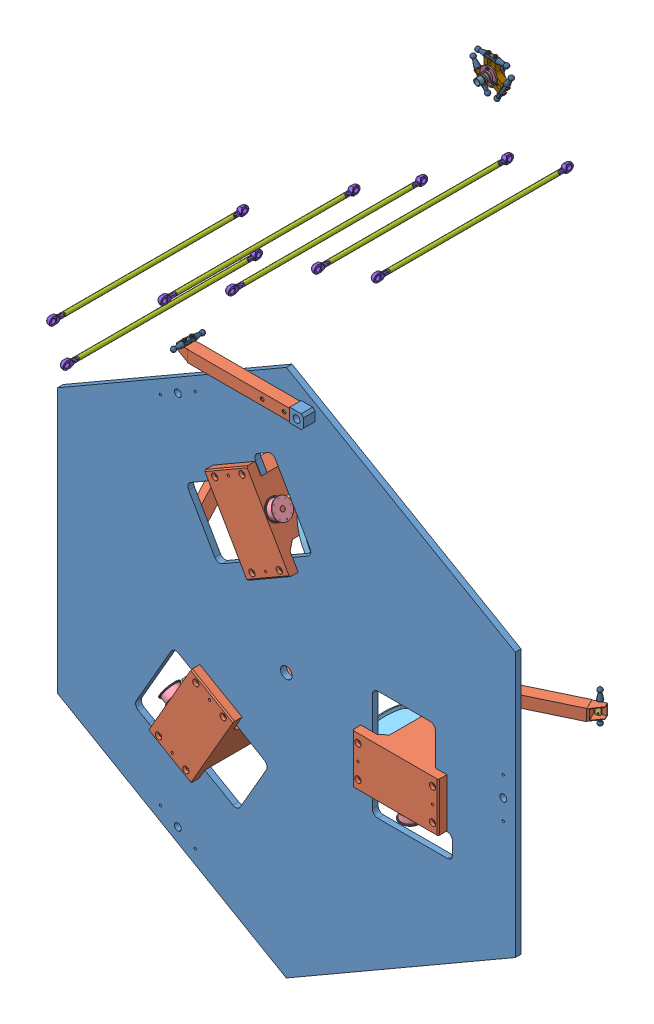
SolidWorks assembly RobotDelta, configuration Défaut. Lengths in mm.
Overall size (971.71 1045.23 749.16).
91 component instances, 22 part files, 18 mates.
Components (placement in the parent):
- Pièce0_Plaque-1: Pièce0_Plaque [Défaut] at origin size (798.48 922 10)
- BlocMoteur-2: BlocMoteur [Défaut] at (214 -99 -18) x (1 0 0) z (0 -1 0) size (260.5 181.1 163)
  - Pièce1_BlocMoteur-1: Pièce1_BlocMoteur [Défaut] at origin size (152.5 162.5 100)
  - Pièce1_PignionModifie-1: Pièce1_PignionModifie [Défaut] x (-0.683299 0.730139 0) z (0 0 1) size (16.65 16.65 16)
  - Pièce1_poulie_renvoie-1: Pièce1_poulie_renvoie [Défaut] at (0 26 0) size (34 34 15)
  - Pièce1_Roue-5: Pièce1_Roue [Défaut] at (-64 -97 0) x (0.958703 0.284409 0) z (0 0 1) size (209.95 116.72 12)
  - Pièce1_arbre-5: Pièce1_arbre [Défaut] at (-64 -97 -42.5) x (0.958703 0.284409 0) z (0 0 1) size (15 15 163)
- BlocMoteur-3: BlocMoteur [Défaut] at (-21.2635 234.8294 -18) x (-0.5 0.866025 0) z (0.866025 0.5 0) size (260.5 181.1 163)
  - Pièce1_BlocMoteur-1: Pièce1_BlocMoteur [Défaut] at origin size (152.5 162.5 100)
  - Pièce1_PignionModifie-1: Pièce1_PignionModifie [Défaut] x (-0.683299 0.730139 0) z (0 0 1) size (16.65 16.65 16)
  - Pièce1_poulie_renvoie-1: Pièce1_poulie_renvoie [Défaut] at (0 26 0) size (34 34 15)
  - Pièce1_Roue-5: Pièce1_Roue [Défaut] at (-64 -97 0) x (0.958703 0.284409 0) z (0 0 1) size (209.95 116.72 12)
  - Pièce1_arbre-5: Pièce1_arbre [Défaut] at (-64 -97 -42.5) x (0.958703 0.284409 0) z (0 0 1) size (15 15 163)
- BlocMoteur-4: BlocMoteur [Défaut] at (-192.7365 -135.8294 -18) x (-0.5 -0.866025 0) z (-0.866025 0.5 0) size (260.5 181.1 163)
  - Pièce1_BlocMoteur-1: Pièce1_BlocMoteur [Défaut] at origin size (152.5 162.5 100)
  - Pièce1_PignionModifie-1: Pièce1_PignionModifie [Défaut] x (-0.683299 0.730139 0) z (0 0 1) size (16.65 16.65 16)
  - Pièce1_poulie_renvoie-1: Pièce1_poulie_renvoie [Défaut] at (0 26 0) size (34 34 15)
  - Pièce1_Roue-5: Pièce1_Roue [Défaut] at (-64 -97 0) x (0.958703 0.284409 0) z (0 0 1) size (209.95 116.72 12)
  - Pièce1_arbre-5: Pièce1_arbre [Défaut] at (-64 -97 -42.5) x (0.958703 0.284409 0) z (0 0 1) size (15 15 163)
- BarreParalleles-6: BarreParalleles [Défaut] at (61.977 576.9928 -569.2096) size (11.85 14 348)
  - Pièce4_Tube-1: Pièce4_Tube [Défaut] at (-2.2142 0.2364 157) size (7 7 314)
  - Pièce4_Extremetees-1: Pièce4_Extremetees [Défaut] at (-2.2142 0.2364 147) x (0 -1 0) z (0 0 1) size (14 11.85 27)
  - Pièce4_Extremetees-2: Pièce4_Extremetees [Défaut] at (-2.2142 0.2364 481) x (0 1 0) z (0 0 -1) size (14 11.85 27)
- BarreParalleles-7: BarreParalleles [Défaut] at (-78.3246 502.1984 -605.2547) size (11.85 14 348)
  - Pièce4_Tube-1: Pièce4_Tube [Défaut] at (-2.2142 0.2364 157) size (7 7 314)
  - Pièce4_Extremetees-1: Pièce4_Extremetees [Défaut] at (-2.2142 0.2364 147) x (0 -1 0) z (0 0 1) size (14 11.85 27)
  - Pièce4_Extremetees-2: Pièce4_Extremetees [Défaut] at (-2.2142 0.2364 481) x (0 1 0) z (0 0 -1) size (14 11.85 27)
- BarreParalleles-8: BarreParalleles [Défaut] at (-192.8024 429.534 -570.0763) size (11.85 14 348)
  - Pièce4_Tube-1: Pièce4_Tube [Défaut] at (-2.2142 0.2364 157) size (7 7 314)
  - Pièce4_Extremetees-1: Pièce4_Extremetees [Défaut] at (-2.2142 0.2364 147) x (0 -1 0) z (0 0 1) size (14 11.85 27)
  - Pièce4_Extremetees-2: Pièce4_Extremetees [Défaut] at (-2.2142 0.2364 481) x (0 1 0) z (0 0 -1) size (14 11.85 27)
- BarreParalleles-9: BarreParalleles [Défaut] at (-314.684 352.2138 -574.0075) size (11.85 14 348)
  - Pièce4_Tube-1: Pièce4_Tube [Défaut] at (-2.2142 0.2364 157) size (7 7 314)
  - Pièce4_Extremetees-1: Pièce4_Extremetees [Défaut] at (-2.2142 0.2364 147) x (0 -1 0) z (0 0 1) size (14 11.85 27)
  - Pièce4_Extremetees-2: Pièce4_Extremetees [Défaut] at (-2.2142 0.2364 481) x (0 1 0) z (0 0 -1) size (14 11.85 27)
- BarreParalleles-10: BarreParalleles [Défaut] at (-485.1921 247.6485 -550.483) size (11.85 14 348)
  - Pièce4_Tube-1: Pièce4_Tube [Défaut] at (-2.2142 0.2364 157) size (7 7 314)
  - Pièce4_Extremetees-1: Pièce4_Extremetees [Défaut] at (-2.2142 0.2364 147) x (0 -1 0) z (0 0 1) size (14 11.85 27)
  - Pièce4_Extremetees-2: Pièce4_Extremetees [Défaut] at (-2.2142 0.2364 481) x (0 1 0) z (0 0 -1) size (14 11.85 27)
- BarreParalleles-11: BarreParalleles [Défaut] at (-563.2574 91.0819 -652.4845) size (11.85 14 348)
  - Pièce4_Tube-1: Pièce4_Tube [Défaut] at (-2.2142 0.2364 157) size (7 7 314)
  - Pièce4_Extremetees-1: Pièce4_Extremetees [Défaut] at (-2.2142 0.2364 147) x (0 -1 0) z (0 0 1) size (14 11.85 27)
  - Pièce4_Extremetees-2: Pièce4_Extremetees [Défaut] at (-2.2142 0.2364 481) x (0 1 0) z (0 0 -1) size (14 11.85 27)
- Nacelle-2: Nacelle [Défaut] at (-284.138 441.1633 -633.2721) size (78.36 68.86 48)
  - Pièce5_Nacelle-1: Pièce5_Nacelle [Défaut] at origin size (49.34 42.73 10)
  - Pièce2_Articulation-1: Pièce2_Articulation [Défaut] at (-20.7846 -12 0) x (-0.5 0.866025 0) z (0 0 1) size (58 9 9)
  - Pièce2_Articulation-2: Pièce2_Articulation [Défaut] at (20.7846 -12 0) x (0.5 0.866025 0) z (0 0 1) size (58 9 9)
  - Pièce2_Articulation-3: Pièce2_Articulation [Défaut] at (0 24 0) x (-1 0 0) z (0 0 1) size (58 9 9)
  - Pièce5_BagueArret-1: Pièce5_BagueArret [Défaut] at (0 0 19) x (-0.629497 -0.777003 0) z (0 0 -1) size (15 15 3)
  - Pièce5_RaccordCardon-1: Pièce5_RaccordCardon [Défaut] at (0 0 -21) x (-0.858461 -0.512879 0) z (0 0 1) size (12 12 11)
  - Pièce5_Capot-1: Pièce5_Capot [Défaut] at (0 0 -11) size (28 28 7)
  - Pièce5_Tube-1: Pièce5_Tube [Défaut] at (0 0 6.5) x (0 0 1) z (0.858461 0.512879 0) size (32 15 15)
  - Pièce5_Capot-2: Pièce5_Capot [Défaut] at (0 0 11) x (0.5 -0.866025 0) z (0 0 -1) size (28 28 7)
  - Pièce5_Guide-1: Pièce5_Guide [Défaut] at (0 0 -3) x (0.858461 0.512879 0) z (0 0 -1) size (12.69 15 12)
  - Pièce5_RaccordTuyau-1: Pièce5_RaccordTuyau [Défaut] at (0 -16.5885 0) x (-1 0 0) z (0 1 0) size (8 24.5 20)
  - Pièce5_ViceTcyM2.5_10-1: Pièce5_ViceTcyM2.5_10 [Défaut] at (-9.5263 -5.5 -9.5) x (0.965811 0.259248 0) z (0 0 1) size (4 4 9.5)
  - Pièce5_ViceTcyM2.5_10-2: Pièce5_ViceTcyM2.5_10 [Défaut] at (9.5263 -5.5 -9.5) x (0.816878 0.576811 0) z (0 0 1) size (4 4 9.5)
  - Pièce5_ViceTcyM2.5_10-3: Pièce5_ViceTcyM2.5_10 [Défaut] at (0 11 -9.5) x (0.152897 -0.988242 0) z (0 0 1) size (4 4 9.5)
  - Pièce5_ViceTcyM3_10-1: Pièce5_ViceTcyM3_10 [Défaut] at (-6 29.5 0) x (1 0 0) z (0 -1 0) size (5.5 5.5 12.5)
  - Pièce5_ViceTcyM3_10-2: Pièce5_ViceTcyM3_10 [Défaut] at (22.5477 -19.9462 0) x (0.25 0.433013 0.866025) z (-0.866025 0.5 0) size (5.5 5.5 12.5)
  - Pièce5_ViceTcyM3_10-3: Pièce5_ViceTcyM3_10 [Défaut] at (28.5477 -9.5538 0) x (0.25 0.433013 0.866025) z (-0.866025 0.5 0) size (5.5 5.5 12.5)
  - Pièce5_ViceTcyM3_10-4: Pièce5_ViceTcyM3_10 [Défaut] at (6 29.5 0) x (1 0 0) z (0 -1 0) size (5.5 5.5 12.5)
  - Pièce5_ViceTcyM3_10-5: Pièce5_ViceTcyM3_10 [Défaut] at (-22.5477 -19.9462 0) x (0.25 -0.433013 -0.866025) z (0.866025 0.5 0) size (5.5 5.5 12.5)
  - Pièce5_ViceTcyM3_10-6: Pièce5_ViceTcyM3_10 [Défaut] at (-28.5477 -9.5538 0) x (-0.102143 0.176917 -0.978911) z (0.866025 0.5 0) size (5.5 5.5 12.5)
  - Pièce5_ViceTcyM2.5_10-4: Pièce5_ViceTcyM2.5_10 [Défaut] at (9.5263 -5.5 9.5) x (-0.923728 -0.383049 0) z (0 0 -1) size (4 4 9.5)
  - Pièce5_ViceTcyM2.5_10-5: Pièce5_ViceTcyM2.5_10 [Défaut] at (0 11 9.5) x (-0.923728 -0.383049 0) z (0 0 -1) size (4 4 9.5)
  - Pièce5_ViceTcyM2.5_10-6: Pièce5_ViceTcyM2.5_10 [Défaut] at (-9.5263 -5.5 9.5) x (-0.923728 -0.383049 0) z (0 0 -1) size (4 4 9.5)
- Bras-1: Bras [Défaut] at (150 10 -115) x (-0.902403 0 0.430893) z (0 -1 0) size (222 30.5 58)
  - Pièce2_support_bras-1: Pièce2_support_bras [Défaut] at origin size (78 24 20)
  - Pièce3_Bras-1: Pièce3_Bras [Défaut] at (-101 10 10) x (-1 0 0) z (0 -1 0) size (198 20 20)
  - Pièce2_Articulation-1: Pièce2_Articulation [Défaut] at (-199.5 13 10) x (0 0 1) z (1 0 0) size (58 9 9)
  - Pièce3_EcrouBras-1: Pièce3_EcrouBras [Défaut] at (-199.5 5.5 10) x (0 0 -1) z (0 1 0) size (17 8 3)
  - Pièce5_ViceTcyM3_10-1: Pièce5_ViceTcyM3_10 [Défaut] at (-199.5 18.5 4) x (-1 0 0) z (0 -1 0) size (5.5 5.5 12.5)
  - Pièce5_ViceTcyM3_10-2: Pièce5_ViceTcyM3_10 [Défaut] at (-199.5 18.5 16) x (-1 0 0) z (0 -1 0) size (5.5 5.5 12.5)
- Bras-2: Bras [Défaut] at (-283.8458 9.3267 -115) x (0.25 -0.433013 0.866025) z (-0.866025 -0.5 0) size (222 30.5 58)
  - Pièce2_support_bras-1: Pièce2_support_bras [Défaut] at origin size (78 24 20)
  - Pièce3_Bras-1: Pièce3_Bras [Défaut] at (-101 10 10) x (-1 0 0) z (0 -1 0) size (198 20 20)
  - Pièce2_Articulation-1: Pièce2_Articulation [Défaut] at (-199.5 13 10) x (0 0 1) z (1 0 0) size (58 9 9)
  - Pièce3_EcrouBras-1: Pièce3_EcrouBras [Défaut] at (-199.5 5.5 10) x (0 0 -1) z (0 1 0) size (17 8 3)
  - Pièce5_ViceTcyM3_10-1: Pièce5_ViceTcyM3_10 [Défaut] at (-199.5 18.5 4) x (-1 0 0) z (0 -1 0) size (5.5 5.5 12.5)
  - Pièce5_ViceTcyM3_10-2: Pièce5_ViceTcyM3_10 [Défaut] at (-199.5 18.5 16) x (-1 0 0) z (0 -1 0) size (5.5 5.5 12.5)
- Bras-3: Bras [Défaut] at (83.8627 457.86 55.8864) size (222 30.5 58)
  - Pièce2_support_bras-1: Pièce2_support_bras [Défaut] at origin size (78 24 20)
  - Pièce3_Bras-1: Pièce3_Bras [Défaut] at (-101 10 10) x (-1 0 0) z (0 -1 0) size (198 20 20)
  - Pièce2_Articulation-1: Pièce2_Articulation [Défaut] at (-199.5 13 10) x (0 0 1) z (1 0 0) size (58 9 9)
  - Pièce3_EcrouBras-1: Pièce3_EcrouBras [Défaut] at (-199.5 5.5 10) x (0 0 -1) z (0 1 0) size (17 8 3)
  - Pièce5_ViceTcyM3_10-1: Pièce5_ViceTcyM3_10 [Défaut] at (-199.5 18.5 4) x (-1 0 0) z (0 -1 0) size (5.5 5.5 12.5)
  - Pièce5_ViceTcyM3_10-2: Pièce5_ViceTcyM3_10 [Défaut] at (-199.5 18.5 16) x (-1 0 0) z (0 -1 0) size (5.5 5.5 12.5)
- Pièce3_BagueBras-1: Pièce3_BagueBras [Défaut] at (150 -10 -115) x (0 -1 0) z (0 0 1) size (4 22 22)
- Pièce3_BagueBras-2: Pièce3_BagueBras [Défaut] at (-66.3397 134.9038 -115) x (0.866025 0.5 0) z (0.168917 -0.292573 0.941206) size (4 22 22)
- Pièce3_BagueBras-3: Pièce3_BagueBras [Défaut] at (-83.6603 -124.9038 -115) x (-0.866025 0.5 0) z (0 0 1) size (4 22 22)
Mates (geometry in assembly coordinates):
- Coaxiale1: concentric anti-aligned: cylinder of Pièce0_Plaque-1 through (140 -84 10) axis (0 0 -1) radius 3; cylinder of BlocMoteur-2/Pièce1_BlocMoteur-1 through (140 -84 19.5) axis (0 0 1) radius 5.5
- Coïncidente1: coincident anti-aligned: plane of Pièce0_Plaque-1 through (0 0 10) normal (0 0 1); plane of BlocMoteur-2/Pièce1_BlocMoteur-1 through (214 -14 10) normal (0 0 -1)
- Coaxiale2: concentric anti-aligned: cylinder of Pièce0_Plaque-1 through (270 -29 10) axis (0 0 -1) radius 3; cylinder of BlocMoteur-2/Pièce1_BlocMoteur-1 through (270 -29 19.5) axis (0 0 1) radius 5.5
- Coaxiale3: concentric anti-aligned: cylinder of Pièce0_Plaque-1 through (-207.7461 -191.8269 10) axis (0 0 -1) radius 3; cylinder of BlocMoteur-4/Pièce1_BlocMoteur-1 through (-207.7461 -191.8269 -3) axis (0 0 1) radius 3.5
- Coïncidente2: coincident anti-aligned: plane of Pièce0_Plaque-1 through (0 0 10) normal (0 0 1); plane of BlocMoteur-4/Pièce1_BlocMoteur-1 through (-119.1244 -178.3294 10) normal (0 0 -1)
- Coaxiale4: concentric anti-aligned: cylinder of Pièce0_Plaque-1 through (-95.1147 -106.7436 10) axis (0 0 -1) radius 3; cylinder of BlocMoteur-4/Pièce1_BlocMoteur-1 through (-95.1147 -106.7436 19.5) axis (0 0 1) radius 5.5
- Coïncidente3: coincident anti-aligned: plane of Pièce0_Plaque-1 through (0 0 10) normal (0 0 1); plane of BlocMoteur-3/Pièce1_BlocMoteur-1 through (-94.8756 192.3294 10) normal (0 0 -1)
- Coaxiale7: concentric anti-aligned: cylinder of Pièce0_Plaque-1 through (-62.2539 275.8269 10) axis (0 0 -1) radius 3; cylinder of BlocMoteur-3/Pièce1_BlocMoteur-1 through (-62.2539 275.8269 19.5) axis (0 0 1) radius 5.5
- Coaxiale8: concentric anti-aligned: cylinder of Pièce0_Plaque-1 through (-44.8853 135.7436 10) axis (0 0 -1) radius 3; cylinder of BlocMoteur-3/Pièce1_BlocMoteur-1 through (-44.8853 135.7436 19.5) axis (0 0 1) radius 5.5
- Coaxiale9: concentric anti-aligned: cylinder of BlocMoteur-2/Pièce1_arbre-5 through (150 -99 -115) axis (0 -1 0) radius 5; cylinder of Bras-1/Pièce2_support_bras-1 through (150 -10 -115) axis (0 1 0) radius 6
- Coïncidente6: coincident anti-aligned: plane of BlocMoteur-2/Pièce1_BlocMoteur-1 through (214 -14 -18) normal (0 1 0); plane of Pièce3_BagueBras-1 through (150 -14 -115) normal (0 -1 0)
- Coaxiale10: concentric anti-aligned: cylinder of BlocMoteur-2/Pièce1_arbre-5 through (150 -99 -115) axis (0 -1 0) radius 5; cylinder of Pièce3_BagueBras-1 through (150 -2.3706 -115) axis (0 1 0) radius 5
- Coïncidente10: coincident anti-aligned: plane of Bras-1/Pièce2_support_bras-1 through (150 -10 -115) normal (0 -1 0); plane of Pièce3_BagueBras-1 through (150 -10 -115) normal (0 1 0)
- Coïncidente15: coincident anti-aligned: plane of BlocMoteur-4/Pièce1_BlocMoteur-1 through (-119.1244 -178.3294 -18) normal (0.866025 -0.5 0); plane of Pièce3_BagueBras-3 through (-87.1244 -122.9038 -115) normal (-0.866025 0.5 0)
- Coaxiale14: concentric anti-aligned: cylinder of BlocMoteur-4/Pièce1_arbre-5 through (-160.7365 -80.4038 -115) axis (-0.866025 0.5 0) radius 5; cylinder of Pièce3_BagueBras-3 through (-77.053 -128.7185 -115) axis (0.866025 -0.5 0) radius 5
- Coïncidente17: coincident anti-aligned: cylinder of BlocMoteur-3/Pièce1_arbre-5 through (10.7365 179.4038 -115) axis (0.866025 0.5 0) radius 5; circle of Pièce3_BagueBras-2
- Coïncidente18: coincident anti-aligned: plane of BlocMoteur-3/Pièce1_BlocMoteur-1 through (-94.8756 192.3294 -18) normal (-0.866025 -0.5 0); plane of Pièce3_BagueBras-2 through (-62.8756 136.9038 -115) normal (0.866025 0.5 0)
- Coaxiale15: concentric anti-aligned: cylinder of BlocMoteur-3/Pièce1_arbre-5 through (10.7365 179.4038 -115) axis (0.866025 0.5 0) radius 5; circle of Bras-2/Pièce2_support_bras-1
